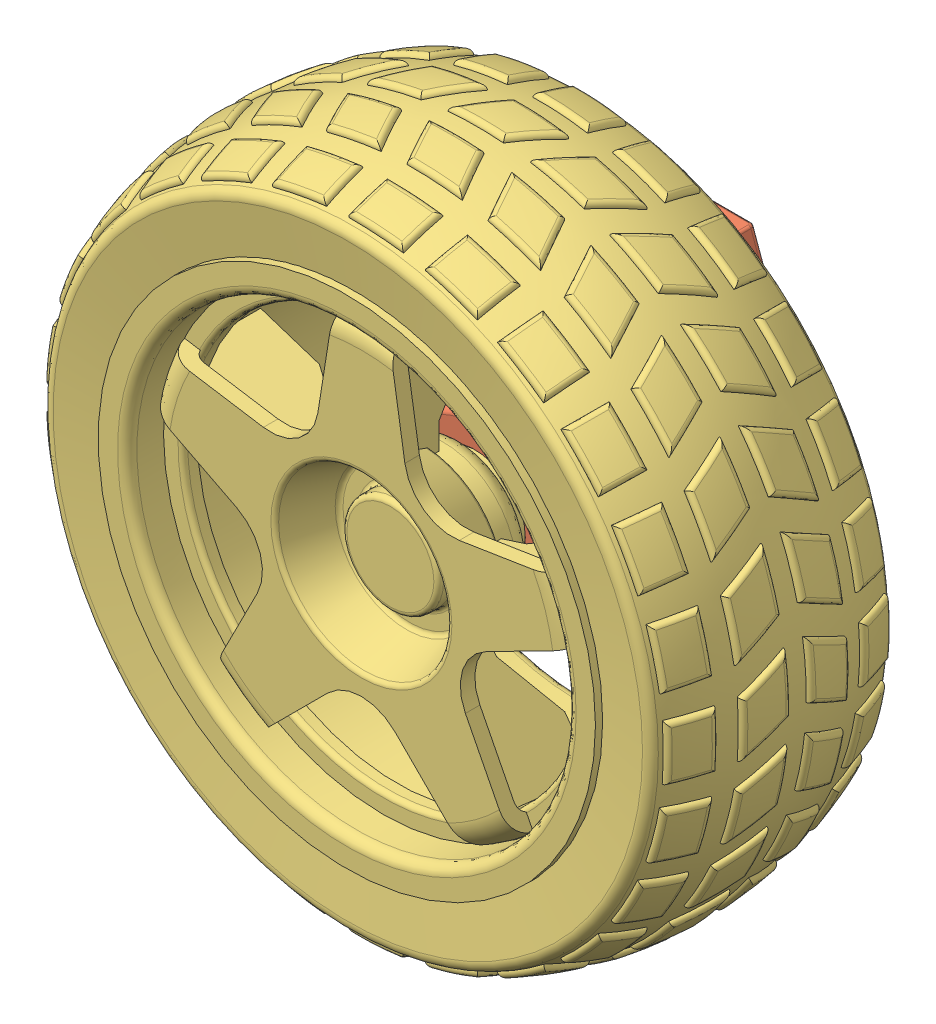
SolidWorks assembly Steer Wheel, configuration Default. Lengths in mm.
Overall size (68.99 69.02 39.2).
3 component instances, 3 part files, 5 mates.
Components (placement in the parent):
- Inner Wheel Connector-1: Inner Wheel Connector [Default] at (0 0 -7) x (0.328119 0.944636 0) z (0 0 1) size (12 12 12)
- Outer Wheel Connector-1: Outer Wheel Connector [Default] at origin size (26 28 26)
- Wheel-1: Wheel [Default] at (0 0 13.2) size (68.99 69.02 30)
Mates (geometry in assembly coordinates):
- Coincident1: coordinate: point of Outer Wheel Connector-1
- Coincident2: coincident anti-aligned: plane of Inner Wheel Connector-1 through (0 0 -15) normal (0 0 1); plane of Wheel-1 through (0 0 -15) normal (0 0 -1)
- Concentric1: concentric aligned: circle of Inner Wheel Connector-1; cylinder of Wheel-1 through (0 0 13.2) axis (0 0 1) radius 4.9
- Coincident3: coincident anti-aligned: plane of Inner Wheel Connector-1 through (-2.5505 0.8859 -17) normal (0 0 1); plane of Outer Wheel Connector-1 through (5.05 0 -17) normal (0 0 -1)
- Concentric2: concentric anti-aligned: circle of Inner Wheel Connector-1; circle of Outer Wheel Connector-1
